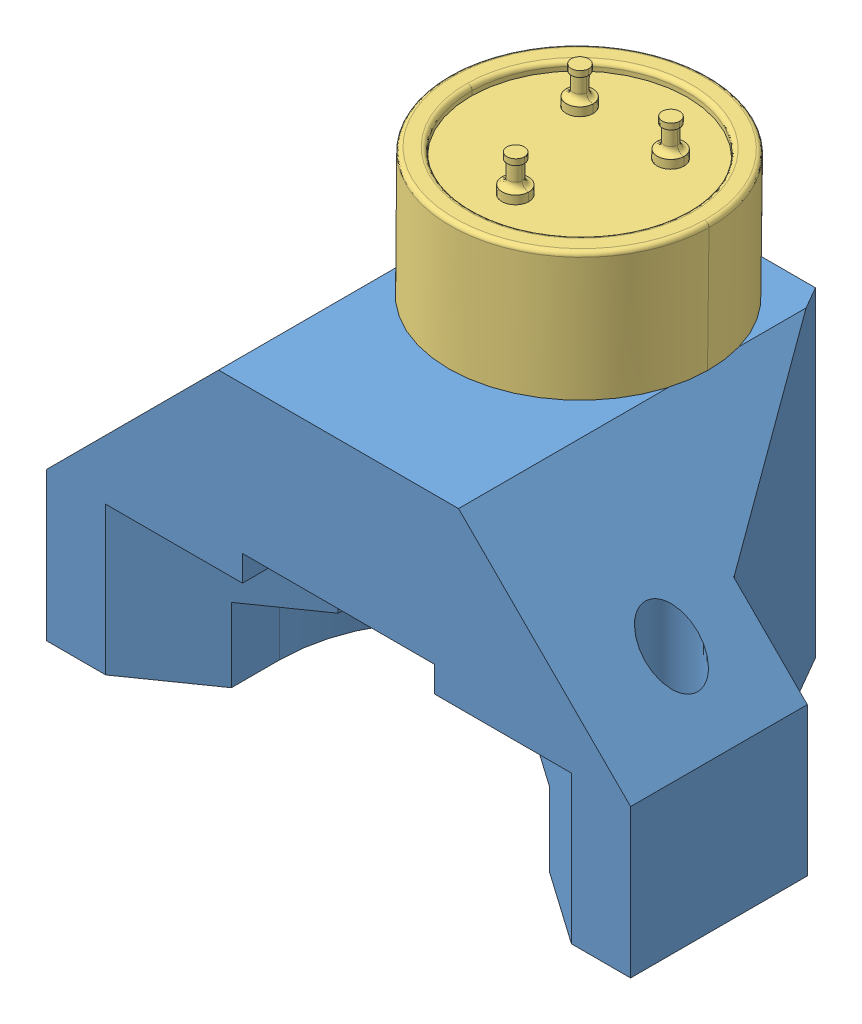
SolidWorks assembly Roll Sensor Asmbly, configuration Default. Lengths in mm.
Overall size (50.16 41.37 31.85).
5 component instances, 4 part files, 3 mates.
Components (placement in the parent):
- Roll Sensor Mount Main-1: Roll Sensor Mount Main [Default] at origin size (50.16 27.53 31.75)
- 94180A351-1: 94180A351 [Default] at (-20 33.3375 99.3144) x (1 0 0) z (0 -1 0) size (6.35 6.35 4.7)
- 94180A351-2: 94180A351 [Default] at (20 33.3375 99.3144) x (1 0 0) z (0 -1 0) size (6.35 6.35 4.7)
- 6127V1AxxxL.5FS-1: 6127V1AxxxL.5FS [6127V1A360L.5FS] at (0 61.2423 87.3281) x (1 0 0) z (0 0.011977 0.999928) size (22.23 35.66 22.23)
- Roll Damper Gear-1: Roll Damper Gear [Default] at (0 38.9173 87.5956) x (-1 0 0) z (0 0.999928 -0.011977) size (14 14 10)
Mates (geometry in assembly coordinates):
- Concentric5: concentric aligned: cylinder of 6127V1AxxxL.5FS-1 through (0 37.5699 87.6117) axis (0 0.999928 -0.011977) radius 3.1712; cylinder of Roll Damper Gear-1 through (0 38.9163 87.5956) axis (0 0.999928 -0.011977) radius 3.2982
- Parallel5: parallel anti-aligned: plane of 6127V1AxxxL.5FS-1 through (-2.3152 48.9426 89.6427) normal (-1 0 0); plane of Roll Damper Gear-1 through (-2.4422 38.9429 89.8121) normal (1 0 0)
- Coincident5: coincident aligned: plane of 6127V1AxxxL.5FS-1 through (0 38.9173 87.5956) normal (0 -0.999928 0.011977); plane of Roll Damper Gear-1 through (0 38.9173 87.5956) normal (0 -0.999928 0.011977)
